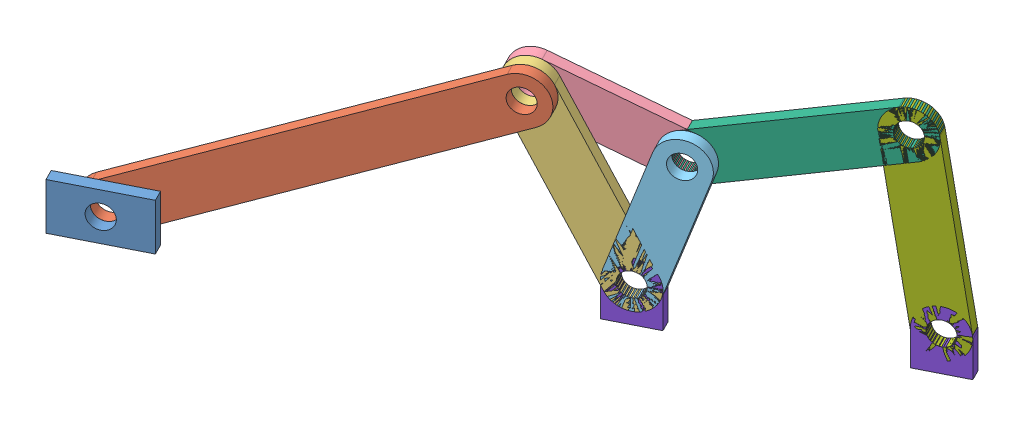
SolidWorks assembly Assem3, configuration Default. Lengths in mm.
Overall size (130.61 52.29 76.04).
9 component instances, 8 part files, 23 mates.
Components (placement in the parent):
- Link2-1: Link2 [Default] at (10.7977 0 112.8639) x (0.89303 0 -0.449997) z (0.449997 0 0.89303) size (17.78 10.16 2.54)
- Link3-1: Link3 [Default] at (21.2233 -2.7273 104.7663) x (-0.792126 -0.461752 0.399151) z (0.449997 0 0.89303) size (86.36 10.16 2.54)
- Link4bc-1: Link4bc [Default] at (92.0375 7.62 66.2389) x (0.413431 -0.886383 -0.208327) z (0.449997 0 0.89303) size (46.99 10.16 2.54)
- Link4bd-1: Link4bd [Default] at (98.2117 31.6621 60.2834) x (0.845289 -0.322586 -0.42594) z (0.449997 0 0.89303) size (36.83 10.16 2.54)
- Link4cd-1: Link4cd [Default] at (99.3547 31.6621 62.5517) x (0.288079 0.94654 -0.145163) z (0.449997 0 0.89303) size (35.56 10.16 2.54)
- Link5-1: Link5 [Default] at (98.2117 31.6621 60.2834) x (0.844387 0.325534 -0.425485) z (0.449997 0 0.89303) size (48.26 10.16 2.54)
- Link6-1: Link6 [Default] at (130.3828 44.065 44.0724) x (0.128793 -0.989546 -0.064898) z (0.449997 0 0.89303) size (46.99 10.16 2.54)
- pin-1: pin [Default] at (132.6493 5.572 42.9304) x (0.89303 0 -0.449997) z (0.449997 0 0.89303) size (10.16 12.7 2.54)
- pin-2: pin [Default] at (89.5605 5.572 67.487) x (0.89303 0 -0.449997) z (0.449997 0 0.89303) size (10.16 12.7 2.54)
Mates (geometry in assembly coordinates):
- Concentric1: concentric aligned: cylinder of Link2-1 through (19.8798 5.08 111.1318) axis (-0.449997 0 -0.89303) radius 2.54; cylinder of Link3-1 through (18.7368 5.08 108.8635) axis (-0.449997 0 -0.89303) radius 2.54
- Coincident1: coincident anti-aligned: plane of Link2-1 through (10.7977 0 112.8639) normal (-0.449997 0 -0.89303); plane of Link3-1 through (18.7368 5.08 108.8635) normal (0.449997 0 0.89303)
- Concentric2: concentric aligned: cylinder of Link3-1 through (79.0968 40.2655 78.4482) axis (-0.449997 0 -0.89303) radius 2.54; cylinder of Link4bc-1 through (77.9538 40.2655 76.1799) axis (-0.449997 0 -0.89303) radius 2.54
- Coincident2: coincident anti-aligned: plane of Link3-1 through (17.5938 5.08 106.5952) normal (-0.449997 0 -0.89303); plane of Link4bc-1 through (93.1805 7.62 68.5072) normal (0.449997 0 0.89303)
- Coincident3: coincident anti-aligned: cylinder of Link4bc-1 through (77.9538 40.2655 76.1799) axis (-0.449997 0 -0.89303) radius 2.54; circle of Link4bd-1
- Coincident4: coincident anti-aligned: plane of Link4bc-1 through (92.0375 7.62 66.2389) normal (-0.449997 0 -0.89303); plane of Link4bd-1 through (99.3547 31.6621 62.5517) normal (0.449997 0 0.89303)
- Coincident5: coincident anti-aligned: cylinder of Link4bc-1 through (93.1805 7.62 68.5072) axis (-0.449997 0 -0.89303) radius 2.54; circle of Link4cd-1
- Coincident6: coincident aligned: plane of Link4bc-1 through (92.0375 7.62 66.2389) normal (-0.449997 0 -0.89303); plane of Link4cd-1 through (99.3547 31.6621 62.5517) normal (-0.449997 0 -0.89303)
- Coincident7: coincident anti-aligned: circle of Link4bd-1; cylinder of Link4cd-1 through (100.4977 31.6621 64.82) axis (-0.449997 0 -0.89303) radius 2.54
- Coincident8: coincident aligned: circle of Link4cd-1; circle of pin-2
- Coincident9: coincident aligned: plane of Link4cd-1 through (100.4977 31.6621 64.82) normal (0.449997 0 0.89303); plane of pin-2 through (93.1805 7.62 68.5072) normal (0.449997 0 0.89303)
- Coincident10: coincident anti-aligned: circle of Link4bd-1; cylinder of Link5-1 through (99.3547 31.6621 62.5517) axis (-0.449997 0 -0.89303) radius 2.54
- Coincident11: coincident anti-aligned: plane of Link4cd-1 through (99.3547 31.6621 62.5517) normal (-0.449997 0 -0.89303); plane of Link5-1 through (99.3547 31.6621 62.5517) normal (0.449997 0 0.89303)
- Coincident12: coincident anti-aligned: circle of Link5-1; cylinder of Link6-1 through (131.5258 44.065 46.3407) axis (-0.449997 0 -0.89303) radius 2.54
- Coincident13: coincident aligned: plane of Link5-1 through (99.3547 31.6621 62.5517) normal (0.449997 0 0.89303); plane of Link6-1 through (131.5258 44.065 46.3407) normal (0.449997 0 0.89303)
- Coincident14: coincident aligned: circle of Link6-1; circle of pin-1
- Parallel1: parallel anti-aligned: plane of Link2-1 through (11.9407 0 115.1322) normal (0 -1 0)
- Coincident15: coincident anti-aligned: plane of Link2-1 through (11.9407 0 115.1322) normal (0 -1 0)
- Coincident16: coincident aligned: plane of pin-2 through (88.6439 0 70.7931) normal (0 -1 0)
- Coincident18: coincident aligned: plane of pin-1 through (131.7327 0 46.2365) normal (0 -1 0)
- Coincident20: coincident aligned: plane of Link4cd-1 through (100.4977 31.6621 64.82) normal (0.449997 0 0.89303); plane of pin-2 through (93.1805 7.62 68.5072) normal (0.449997 0 0.89303)
- Coincident23: coincident aligned: plane of Link6-1 through (131.5258 44.065 46.3407) normal (0.449997 0 0.89303); plane of pin-1 through (136.2693 7.62 43.9505) normal (0.449997 0 0.89303)
- Distance1: distance = 49.53 mm aligned: plane of pin-2 through (97.717 0 66.2212) normal (0.89303 0 -0.449997); plane of pin-1 through (140.8058 0 41.6646) normal (0.89303 0 -0.449997)
